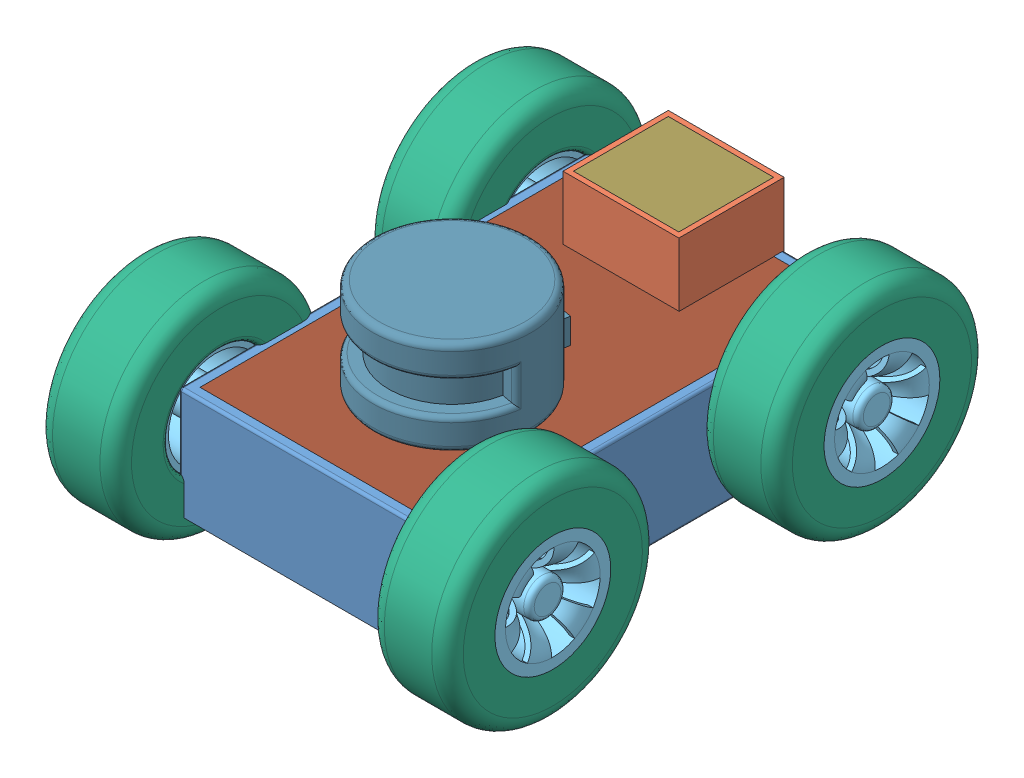
SolidWorks assembly Autonomous navigation bot, configuration Default. Lengths in mm.
Overall size (78.01 58.52 121.02).
38 component instances, 14 part files, 36 mates.
Components (placement in the parent):
- Aries project-1: Aries project [Default] at (-2.6274 21.9216 65.6391) size (50 21 80)
- Diffferential motor aries-1: Diffferential motor aries [Default] at (15.966 13.683 6.9864) x (1 0 0) z (0 1 0) size (25.45 26.52 31.2)
  - Differential box-1: Differential box [Default] at (5.3507 11.3329 9.2636) size (22 20 27)
  - Aries project Differential-1: Aries project Differential [Default] at (-7.0512 31.8112 15.5431) x (0.98773 0.030546 -0.153154) z (0.155913 -0.249109 0.955843) size (22.74 20.21 25.25)
    - Differential part 1-3: Differential part 1 [Default] at (6.6336 -19.3941 6.6309) x (0.98773 0.008955 0.155913) z (0.064078 -0.933684 -0.352318) size (10.65 13.87 13.91)
    - Differential part 2-4: Differential part 2 [Default] at (11.5308 -21.8615 6.8199) x (0.98773 0.008955 0.155913) z (-0.120067 0.681953 0.721474) size (9.81 5.94 5.96)
      - straight bevel gear_iso-1: straight bevel gear_iso [ISO - Straight bevel gear 0.3M 19GT 12PT 14.5PA 7FW ---19O3H10MD0.8N] at (-3.5446 0.6303 2.0777) size (9.81 5.94 5.96)
    - Differential part 2-5: Differential part 2 [Default] at (9.6513 -21.0712 6.6203) x (0.142419 0.357986 -0.922802) z (0.893588 0.354464 0.275419) size (9.81 5.94 5.96)
      - straight bevel gear_iso-1: straight bevel gear_iso [ISO - Straight bevel gear 0.3M 19GT 12PT 14.5PA 7FW ---19O3H10MD0.8N] at (-3.5446 0.6303 2.0777) size (9.81 5.94 5.96)
    - Differential part 2-6: Differential part 2 [Default] at (13.2252 -20.4695 8.5856) x (-0.142419 -0.357986 0.922802) z (-0.968764 -0.1408 -0.204134) size (9.81 5.94 5.96)
      - straight bevel gear_iso-1: straight bevel gear_iso [ISO - Straight bevel gear 0.3M 19GT 12PT 14.5PA 7FW ---19O3H10MD0.8N] at (-3.5446 0.6303 2.0777) size (9.81 5.94 5.96)
    - Differential part 2-7: Differential part 2 [Default] at (10.6434 -18.1036 6.6974) x (-0.98773 -0.008955 -0.155913) z (-0.106959 -0.688662 0.71715) size (9.81 5.94 5.96)
      - straight bevel gear_iso-1: straight bevel gear_iso [ISO - Straight bevel gear 0.3M 19GT 12PT 14.5PA 7FW ---19O3H10MD0.8N] at (-3.5446 0.6303 2.0777) size (9.81 5.94 5.96)
    - Differential part 1-4: Differential part 1 [Default] at (12.2662 -18.8312 15.7512) x (0.153433 -0.241744 -0.958133) z (0.933412 -0.282803 0.220828) size (7.08 13.87 13.91)
      - straight bevel gear_iso-4: straight bevel gear_iso [ISO - Straight bevel gear 0.7M 19GT 12PT 14.5PA 1.6FW ---19O10H10MD0.8N] at (0.225 0.7054 0.4074) size (7.08 13.87 13.91)
- Aries project wheel-2: Aries project wheel [Default] at (56.6523 5.1697 55.7651) x (1 0 0) z (0 0.731725 0.6816) size (15 45.35 45.35)
  - Aries Project rim-1: Aries Project rim [Default] at (-2.2797 14.8361 20.1437) size (14 22 22)
  - Aries poject wheel ext-1: Aries poject wheel ext [Default] at (4.7228 14.8361 20.1437) x (0 0.144321 0.989531) z (-1 0 0) size (40 40 15)
- Aries project wheel-3: Aries project wheel [Default] at (-11.9072 44.7547 78.8582) x (-1 0 0) z (0 -0.953464 -0.301506) size (15 45.35 45.35)
  - Aries Project rim-1: Aries Project rim [Default] at (-2.2797 14.8361 20.1437) size (14 22 22)
  - Aries poject wheel ext-1: Aries poject wheel ext [Default] at (4.7228 14.8361 20.1437) x (0 0.144321 0.989531) z (-1 0 0) size (40 40 15)
- Aries project wheel-6: Aries project wheel [Default] at (-11.9072 44.5933 -24.1967) x (-1 0 0) z (0 0.013064 0.999915) size (15 45.35 45.35)
  - Aries Project rim-1: Aries Project rim [Default] at (-2.2797 14.8361 20.1437) size (14 22 22)
  - Aries poject wheel ext-1: Aries poject wheel ext [Default] at (4.7228 14.8361 20.1437) x (0 0.144321 0.989531) z (-1 0 0) size (40 40 15)
- Aries project wheel-7: Aries project wheel [Default] at (56.6523 42.2719 -25.674) x (1 0 0) z (0 -0.911339 0.411657) size (15 45.35 45.35)
  - Aries Project rim-1: Aries Project rim [Default] at (-2.2797 14.8361 20.1437) size (14 22 22)
  - Aries poject wheel ext-1: Aries poject wheel ext [Default] at (4.7228 14.8361 20.1437) x (0 0.144321 0.989531) z (-1 0 0) size (40 40 15)
- rod 1 -1: rod 1  [Default] at (-2.6274 30.0216 -3.8609) x (0 0.252682 0.967549) z (0 0.967549 -0.252682) size (3 14 3)
- rod2-1: rod2 [Default] at (-3.6274 30.0216 -3.8609) x (0 -0.999583 -0.028872) z (0 -0.028872 0.999583) size (5 3 5)
- rod2-2: rod2 [Default] at (45.3726 30.0216 -3.8609) x (0 -0.982361 -0.186994) z (0 -0.186994 0.982361) size (5 3 5)
- rod 3-1: rod 3 [Default] at (-2.6274 30.0216 58.6391) x (0 -1 0) z (0 0 1) size (3 50 3)
- rod2-4: rod2 [Default] at (-3.6274 30.0216 58.6391) x (0 -0.828033 -0.560679) z (0 -0.560679 0.828033) size (5 3 5)
- rod2-6: rod2 [Default] at (48.3726 30.0216 58.6391) x (0 0.075944 -0.997112) z (0 0.997112 0.075944) size (5 3 5)
- rod 4-1: rod 4 [Default] at (47.3726 30.0216 -3.8609) x (0 0.218474 -0.975843) z (0 0.975843 0.218474) size (3 15.78 3)
- Autonomous navigation bot cover-1: Autonomous navigation bot cover [Default] at (45.3726 34.9216 63.6391) x (0 0 -1) z (1 0 0) size (76 2 46)
- cover-1: cover [Default] at (11.3167 47.9466 4.6535) size (20 1 18)
- rasberrypie-2: rasberrypie [Default] at (9.3726 17.1216 22.0707) size (20 1.2 10)
- lidar-1: lidar [Default] at (23.3582 15.9817 41.5387) x (-0.983415 0 -0.18137) z (-0.18137 0 0.983415) size (30 18 32.1)
Mates (geometry in assembly coordinates):
- Concentric1: concentric anti-aligned: circle of Aries project-1; circle of Diffferential motor aries-1/Differential box-1
- Parallel1: parallel anti-aligned: plane of Aries project-1 through (-0.6274 31.9216 63.6391) normal (1 0 0); plane of Diffferential motor aries-1/Differential box-1 through (10.3167 32.9466 5.6535) normal (-1 0 0)
- Parallel2: parallel anti-aligned: plane of Aries project-1 through (-0.6274 31.9216 -12.3609) normal (0 0 1); plane of Diffferential motor aries-1/Differential box-1 through (10.3167 32.9466 -14.3465) normal (0 0 -1)
- Concentric2: concentric anti-aligned: circle of Aries project-1; circle of Aries project wheel-2/Aries Project rim-1
- Coincident4: coincident anti-aligned: circle of Aries project-1; circle of Aries project wheel-3/Aries Project rim-1
- Concentric3: concentric anti-aligned: circle of Aries project-1; circle of Aries project wheel-6/Aries Project rim-1
- Coincident7: coincident anti-aligned: plane of Aries project-1 through (-2.6274 16.9216 65.6391) normal (-1 0 0); circle of Aries project wheel-6/Aries Project rim-1
- Concentric4: concentric anti-aligned: circle of Aries project-1; circle of Aries project wheel-7/Aries Project rim-1
- Coincident8: coincident anti-aligned: plane of Aries project-1 through (47.3726 16.9216 65.6391) normal (1 0 0); circle of Aries project wheel-7/Aries Project rim-1
- Coincident9: coincident anti-aligned: plane of Aries project-1 through (47.3726 16.9216 65.6391) normal (1 0 0); circle of Aries project wheel-2/Aries Project rim-1
- Concentric5: concentric aligned: circle of Diffferential motor aries-1/Differential box-1; circle of rod 1 -1
- Coincident15: coincident anti-aligned: plane of Diffferential motor aries-1/Aries project Differential-1/Differential part 2-4/straight bevel gear_iso-1 through (11.3726 30.0216 -3.8609) normal (-1 0 0); plane of rod 1 -1 through (11.3726 30.0216 -3.8609) normal (1 0 0)
- Coincident16: coincident aligned: plane of Aries project-1 through (-2.6274 16.9216 65.6391) normal (-1 0 0); plane of rod 1 -1 through (-2.6274 30.0216 -3.8609) normal (-1 0 0)
- Concentric6: concentric anti-aligned: cylinder of Aries project-1 through (-13.6274 30.0216 -3.8609) axis (1 0 0) radius 2.5; cylinder of rod2-1 through (-0.6274 30.0216 -3.8609) axis (-1 0 0) radius 2.5
- Concentric7: concentric anti-aligned: circle of Aries project-1; cylinder of rod2-2 through (48.3726 30.0216 -3.8609) axis (-1 0 0) radius 2.5
- Coincident21: coincident aligned: plane of Aries project-1 through (-0.6274 31.9216 63.6391) normal (1 0 0); plane of rod2-1 through (-0.6274 30.0216 -3.8609) normal (1 0 0)
- Coincident22: coincident anti-aligned: plane of Aries project-1 through (45.3726 31.9216 63.6391) normal (-1 0 0); circle of rod2-2
- Concentric8: concentric anti-aligned: circle of Aries project-1; circle of rod 3-1
- Coincident23: coincident aligned: plane of Aries project-1 through (-2.6274 16.9216 65.6391) normal (-1 0 0); plane of rod 3-1 through (-2.6274 30.0216 58.6391) normal (-1 0 0)
- Concentric9: concentric aligned: circle of Aries project-1; cylinder of rod2-4 through (-0.6274 30.0216 58.6391) axis (-1 0 0) radius 2.5
- Coincident24: coincident aligned: plane of Aries project-1 through (-0.6274 31.9216 63.6391) normal (1 0 0); plane of rod2-4 through (-0.6274 30.0216 58.6391) normal (1 0 0)
- Concentric10: concentric aligned: circle of Aries project-1; cylinder of rod2-6 through (45.3726 30.0216 58.6391) axis (1 0 0) radius 2.5
- Coincident25: coincident aligned: plane of Aries project-1 through (45.3726 31.9216 63.6391) normal (-1 0 0); plane of rod2-6 through (45.3726 30.0216 58.6391) normal (-1 0 0)
- Concentric11: concentric anti-aligned: circle of Diffferential motor aries-1/Differential box-1; circle of rod 4-1
- Coincident27: coincident aligned: plane of Aries project-1 through (47.3726 16.9216 65.6391) normal (1 0 0); plane of rod 4-1 through (47.3726 30.0216 -3.8609) normal (1 0 0)
- GearMate1: gear = 40 : 3 mm: cylinder of rod 1 -1 through (11.3726 30.0216 -3.8609) axis (-1 0 0) radius 1.5; cylinder of Aries project wheel-6/Aries poject wheel ext-1 through (-1.63 30.0216 -3.8609) axis (-1 0 0) radius 20
- GearMate2: gear = 10 : 3 mm: cylinder of rod 1 -1 through (11.3726 30.0216 -3.8609) axis (-1 0 0) radius 1.5; cylinder of Diffferential motor aries-1/Aries project Differential-1/Differential part 1-3 through (11.8365 30.0216 -3.8609) axis (1 0 0) radius 5
- Coincident28: coincident anti-aligned: plane of Aries project-1 through (-0.6274 31.9216 63.6391) normal (0 0 -1); plane of Autonomous navigation bot cover-1 through (45.3726 36.9216 63.6391) normal (0 0 1)
- Coincident29: coincident aligned: line of Aries project-1 through (-0.6274 36.9216 63.6391) axis (1 0 0); line of Autonomous navigation bot cover-1 through (-0.6274 36.9216 63.6391) axis (1 0 0)
- Coincident30: coincident aligned: line of Aries project-1 through (45.3726 36.9216 63.6391) axis (0 0 -1); line of Autonomous navigation bot cover-1 through (45.3726 36.9216 63.6391) axis (0 0 -1)
- Coincident31: coincident anti-aligned: plane of Diffferential motor aries-1/Differential box-1 through (11.3167 32.9466 4.6535) normal (0 0 -1); plane of cover-1 through (11.3167 48.9466 4.6535) normal (0 0 1)
- Coincident32: coincident aligned: line of Diffferential motor aries-1/Differential box-1 through (11.3167 48.9466 4.6535) axis (1 0 0); line of cover-1 through (11.3167 48.9466 4.6535) axis (1 0 0)
- Coincident33: coincident aligned: line of Diffferential motor aries-1/Differential box-1 through (11.3167 48.9466 -13.3465) axis (0 0 1); line of cover-1 through (11.3167 48.9466 -13.3465) axis (0 0 1)
- Coincident34: coincident anti-aligned: plane of Aries project-1 through (-2.6274 16.9216 65.6391) normal (0 1 0); plane of rasberrypie-2 through (9.3726 16.9216 22.0707) normal (0 -1 0)
- Coincident35: coincident: plane of Aries project-1 through (-0.6274 31.9216 63.6391) normal (1 0 0); line of rasberrypie-2 through (-0.6274 17.1216 27.0707) axis (0 0 -1)
- Coincident38: coincident anti-aligned: plane of Autonomous navigation bot cover-1 through (45.3726 36.9216 63.6391) normal (0 1 0); plane of lidar-1 through (23.6352 36.9216 40.0288) normal (0 -1 0)
